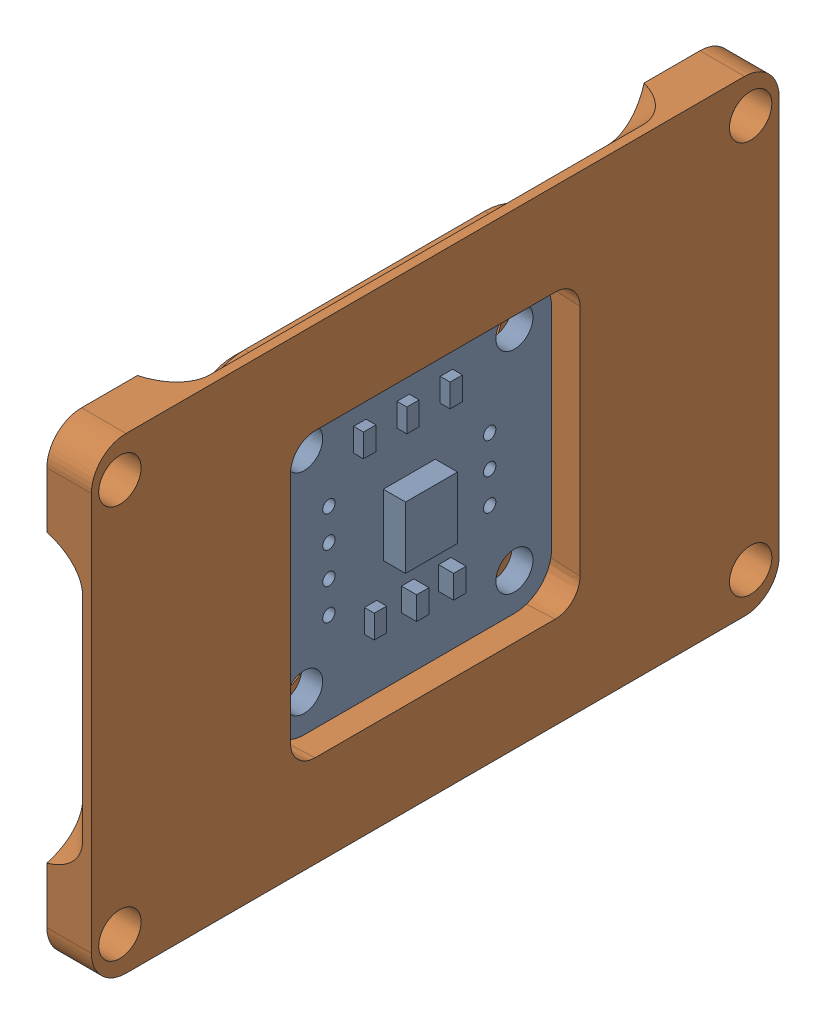
SolidWorks assembly Encoder_3__1, configuration Default. Lengths in mm.
Overall size (6.6 37.8 55.6).
2 component instances, 2 part files, 0 mates.
Components (placement in the parent):
- AS5600_1-1: AS5600_1 [Default] at (-84.2 -23.5 242.5) x (0 1 0) z (0 0 -1) size (23 3.5 23)
- EncoderHousing_1-1: EncoderHousing_1 [Default] at (-81.9 -23.5 242.5) x (0 1 0) z (1 0 0) size (37.8 55.6 6.6)
